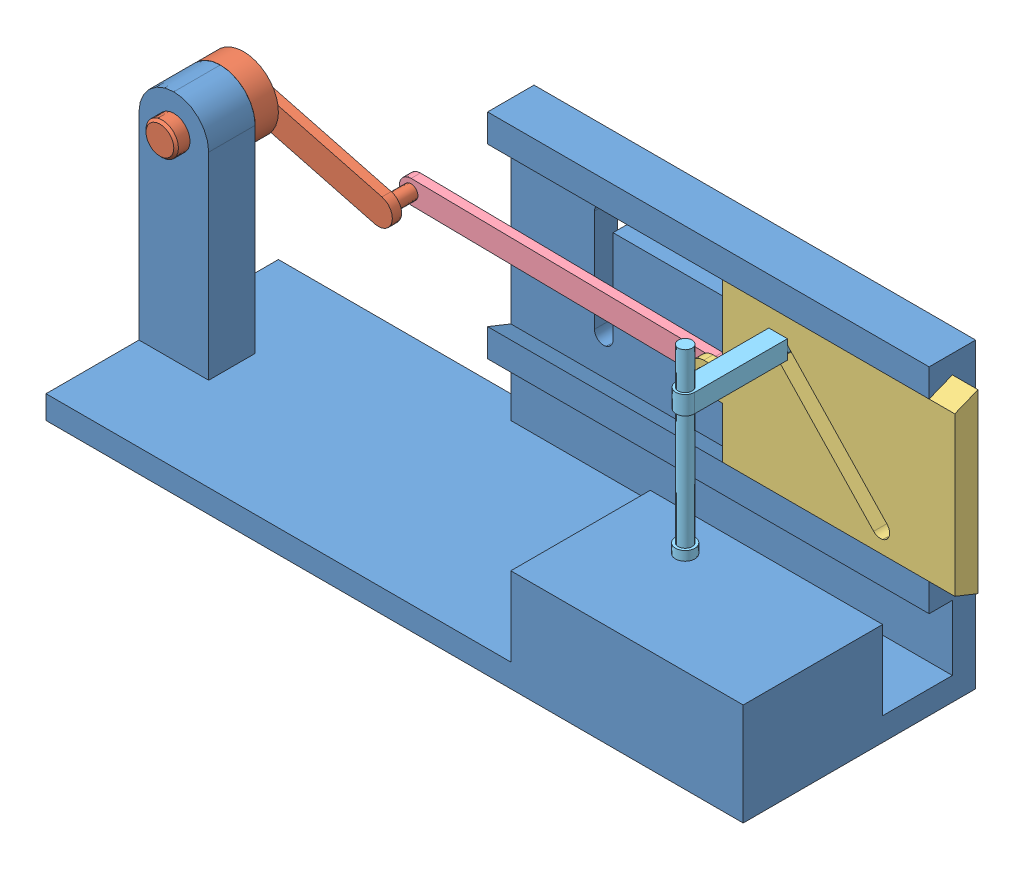
SolidWorks assembly Assem4, configuration Default. Lengths in mm.
Overall size (157.17 65 52).
5 component instances, 5 part files, 11 mates.
Components (placement in the parent):
- Part5-1: Part5 [Default] at (-40.0617 29.8539 165.2719) size (150 65 50)
- Part6-1: Part6 [Default] at (-32.5617 77.3539 130.2719) x (0.253452 0.967348 0) z (0 0 1) size (15 40.5 25)
- Part7-1: Part7 [Default] at (115.4526 52.8539 120.2719) x (0 0 1) z (-1 0 0) size (5 38 57)
- Part8-1: Part8 [Default] at (61.4526 68.8539 121.2719) x (0.999905 -0.013791 0) z (0 0 1) size (70 5 2)
- Part9-1: Part9 [Default] at (77.4526 80.8539 145.2719) size (4.17 39 34.09)
Mates (geometry in assembly coordinates):
- Concentric1: concentric anti-aligned: cylinder of Part5-1 through (-32.5617 77.3539 115.2719) axis (0 0 1) radius 3.5; cylinder of Part6-1 through (-32.5617 77.3539 148.2719) axis (0 0 -1) radius 3.5
- Coincident1: coincident anti-aligned: plane of Part5-1 through (-40.0617 84.8539 135.2719) normal (0 0 -1); plane of Part6-1 through (-32.5617 77.3539 135.2719) normal (0 0 1)
- Coincident2: coincident anti-aligned: plane of Part5-1 through (14.9383 94.8539 120.2719) normal (0 0 1); plane of Part7-1 through (65.4526 90.8539 120.2719) normal (0 0 -1)
- Coincident3: coincident anti-aligned: plane of Part5-1 through (7.1281 54.8539 125.2719) normal (0 0.928477 -0.371391); plane of Part7-1 through (65.4526 52.8539 120.2719) normal (0 -0.928477 0.371391)
- Concentric2: concentric anti-aligned: cylinder of Part6-1 through (-3.5412 69.7504 123.2719) axis (0 0 1) radius 1.5; cylinder of Part8-1 through (-3.5412 69.7504 123.2719) axis (0 0 -1) radius 1.5
- Concentric3: concentric anti-aligned: cylinder of Part7-1 through (61.4526 68.8539 123.2719) axis (0 0 1) radius 1.5; cylinder of Part8-1 through (61.4526 68.8539 123.2719) axis (0 0 -1) radius 1.5
- Coincident5: coincident anti-aligned: plane of Part7-1 through (65.4526 68.8539 123.2719) normal (0 0 -1); plane of Part8-1 through (61.4526 68.8539 123.2719) normal (0 0 1)
- Parallel1: parallel aligned: plane of Part5-1 through (-40.0617 94.8539 165.2719) normal (0 1 0); plane of Part9-1 through (77.4526 84.8539 145.2719) normal (0 1 0)
- Coincident7: coincident anti-aligned: plane of Part7-1 through (65.4526 54.8539 125.2719) normal (0 0 1); plane of Part9-1 through (75.4526 53.8539 125.2719) normal (0 0 -1)
- PathMate2: path: point of Part9-1; curve of Part5-1; curve of Part5-1
- Tangent7: tangent anti-aligned: plane of Part7-1 through (78.9049 84.2289 120.2719) normal (-0.726184 -0.6875 0); cylinder of Part9-1 through (77.4526 82.8539 113.2719) axis (0 0 1) radius 2
